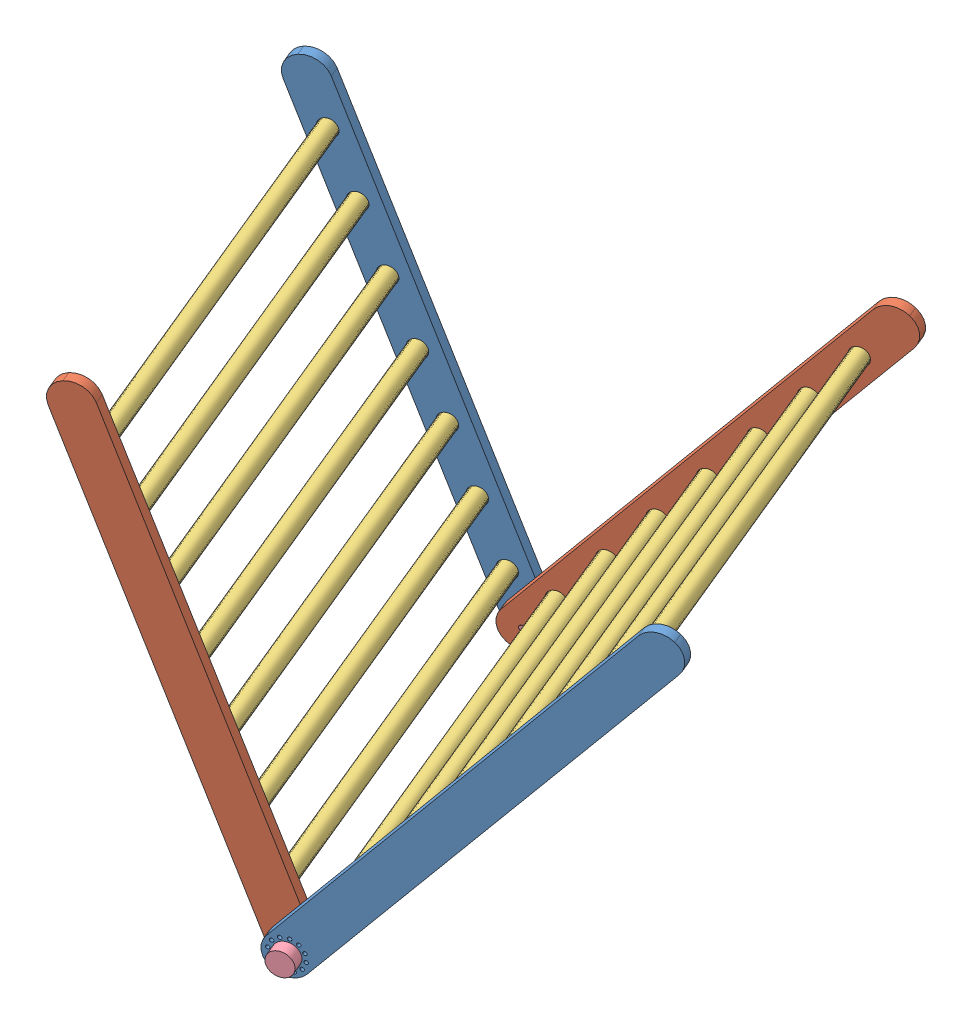
SolidWorks assembly Assembly, configuration Default. Lengths in mm.
Overall size (1185.17 985.62 1062.37).
20 component instances, 4 part files, 28 mates.
Components (placement in the parent):
- Leg Radial Locking Holes-1: Leg Radial Locking Holes [Default] at (-779.6001 -1481.6632 618.7852) x (0.61301 0.769332 -0.179852) z (0.350411 -0.060717 0.934626) size (965.2 76.2 19.05)
- Leg Single Locking Hole-1: Leg Single Locking Hole [Default] at (-758.4501 -1524.0941 587.7167) x (-0.297342 0.939062 0.172485) z (0.350411 -0.060717 0.934626) size (965.2 76.2 19.05)
- Leg Single Locking Hole-3: Leg Single Locking Hole [Default] at (-985.9797 -1485.0135 -98.9733) x (0.61301 0.769332 -0.179852) z (-0.350411 0.060717 -0.934626) size (965.2 76.2 19.05)
- Leg Radial Locking Holes-2: Leg Radial Locking Holes [Default] at (-951.1116 -1453.2027 -130.3621) x (-0.297342 0.939062 0.172485) z (-0.350411 0.060717 -0.934626) size (965.2 76.2 19.05)
- Dowel-2: Dowel [Default] at (-1024.1619 -1352.2175 -106.6048) x (0.936531 0.010997 -0.350411) z (0.350411 -0.060717 0.934626) size (31.75 31.75 762)
- Dowel-3: Dowel [Default] at (-1095.9105 -1125.6219 -64.9842) x (0.936531 0.010997 -0.350411) z (0.350411 -0.060717 0.934626) size (31.75 31.75 762)
- Dowel-4: Dowel [Default] at (-1167.6591 -899.0263 -23.3635) x (0.936531 0.010997 -0.350411) z (0.350411 -0.060717 0.934626) size (31.75 31.75 762)
- Dowel-5: Dowel [Default] at (-1203.5334 -785.7285 -2.5532) x (0.936531 0.010997 -0.350411) z (0.350411 -0.060717 0.934626) size (31.75 31.75 762)
- Dowel-6: Dowel [Default] at (-1239.4077 -672.4307 18.2571) x (0.936531 0.010997 -0.350411) z (0.350411 -0.060717 0.934626) size (31.75 31.75 762)
- Dowel-7: Dowel [Default] at (-1060.0362 -1238.9197 -85.7945) x (0.936531 0.010997 -0.350411) z (0.350411 -0.060717 0.934626) size (31.75 31.75 762)
- Dowel-8: Dowel [Default] at (-1131.7848 -1012.3241 -44.1739) x (0.936531 0.010997 -0.350411) z (0.350411 -0.060717 0.934626) size (31.75 31.75 762)
- knob-1: knob [Default] at (-722.5898 -1477.7383 618.0483) x (-0.928635 -0.152357 0.338268) z (0.350411 -0.060717 0.934626) size (44.45 44.45 60.45)
- knob-2: knob [Default] at (-1002.954 -1429.1587 -129.7457) x (0.546294 -0.797315 -0.256614) z (-0.350411 0.060717 -0.934626) size (44.45 44.45 60.45)
- Dowel-9: Dowel [Default] at (-498.5792 -810.4656 -248.0803) x (0.936531 0.010997 -0.350411) z (0.350411 -0.060717 0.934626) size (31.75 31.75 762)
- Dowel-10: Dowel [Default] at (-572.5388 -903.2855 -226.3812) x (0.936531 0.010997 -0.350411) z (0.350411 -0.060717 0.934626) size (31.75 31.75 762)
- Dowel-11: Dowel [Default] at (-646.4985 -996.1055 -204.6821) x (0.936531 0.010997 -0.350411) z (0.350411 -0.060717 0.934626) size (31.75 31.75 762)
- Dowel-12: Dowel [Default] at (-720.4581 -1088.9254 -182.983) x (0.936531 0.010997 -0.350411) z (0.350411 -0.060717 0.934626) size (31.75 31.75 762)
- Dowel-13: Dowel [Default] at (-794.4177 -1181.7454 -161.2838) x (0.936531 0.010997 -0.350411) z (0.350411 -0.060717 0.934626) size (31.75 31.75 762)
- Dowel-14: Dowel [Default] at (-868.3774 -1274.5653 -139.5847) x (0.936531 0.010997 -0.350411) z (0.350411 -0.060717 0.934626) size (31.75 31.75 762)
- Dowel-15: Dowel [Default] at (-942.337 -1367.3853 -117.8856) x (0.936531 0.010997 -0.350411) z (0.350411 -0.060717 0.934626) size (31.75 31.75 762)
Mates (geometry in assembly coordinates):
- Concentric1: concentric aligned: cylinder of Leg Radial Locking Holes-1 through (-722.5898 -1477.7383 618.0483) axis (-0.350411 0.060717 -0.934626) radius 4.9609; cylinder of Leg Single Locking Hole-1 through (-729.2652 -1476.5816 600.2437) axis (-0.350411 0.060717 -0.934626) radius 4.9609
- Concentric2: concentric aligned: cylinder of Leg Single Locking Hole-3 through (-996.2786 -1430.3153 -111.9411) axis (0.350411 -0.060717 0.934626) radius 4.9609; cylinder of Leg Radial Locking Holes-2 through (-1002.954 -1429.1587 -129.7457) axis (0.350411 -0.060717 0.934626) radius 4.9609
- Coincident3: coincident aligned: cylinder of Leg Radial Locking Holes-1 through (-722.5898 -1477.7383 618.0483) axis (-0.350411 0.060717 -0.934626) radius 4.9609; circle of Leg Radial Locking Holes-2
- Concentric3: concentric anti-aligned: circle of Leg Radial Locking Holes-2; circle of Dowel-2
- Coincident6: coincident anti-aligned: plane of Leg Radial Locking Holes-2 through (-954.4493 -1452.6243 -139.2644) normal (0.350411 -0.060717 0.934626); plane of Dowel-2 through (-1024.1619 -1352.2175 -106.6048) normal (-0.350411 0.060717 -0.934626)
- Coincident7: coincident anti-aligned: plane of Leg Single Locking Hole-1 through (-755.1124 -1524.6725 596.619) normal (-0.350411 0.060717 -0.934626); plane of Dowel-2 through (-757.1484 -1398.4838 605.58) normal (0.350411 -0.060717 0.934626)
- Coincident8: coincident anti-aligned: plane of Leg Radial Locking Holes-2 through (-954.4493 -1452.6243 -139.2644) normal (0.350411 -0.060717 0.934626); plane of Dowel-7 through (-1060.0362 -1238.9197 -85.7945) normal (-0.350411 0.060717 -0.934626)
- Concentric5: concentric anti-aligned: circle of Leg Radial Locking Holes-2; circle of Dowel-7
- Coincident9: coincident anti-aligned: plane of Leg Radial Locking Holes-2 through (-954.4493 -1452.6243 -139.2644) normal (0.350411 -0.060717 0.934626); plane of Dowel-3 through (-1095.9105 -1125.6219 -64.9842) normal (-0.350411 0.060717 -0.934626)
- Concentric6: concentric anti-aligned: circle of Leg Radial Locking Holes-2; circle of Dowel-3
- Coincident10: coincident anti-aligned: plane of Leg Radial Locking Holes-2 through (-954.4493 -1452.6243 -139.2644) normal (0.350411 -0.060717 0.934626); plane of Dowel-8 through (-1131.7848 -1012.3241 -44.1739) normal (-0.350411 0.060717 -0.934626)
- Concentric7: concentric anti-aligned: circle of Leg Radial Locking Holes-2; circle of Dowel-8
- Coincident11: coincident anti-aligned: plane of Leg Radial Locking Holes-2 through (-954.4493 -1452.6243 -139.2644) normal (0.350411 -0.060717 0.934626); plane of Dowel-4 through (-1167.6591 -899.0263 -23.3635) normal (-0.350411 0.060717 -0.934626)
- Concentric8: concentric anti-aligned: circle of Leg Radial Locking Holes-2; circle of Dowel-4
- Coincident13: coincident anti-aligned: plane of Leg Radial Locking Holes-2 through (-954.4493 -1452.6243 -139.2644) normal (0.350411 -0.060717 0.934626); plane of Dowel-5 through (-1203.5334 -785.7285 -2.5532) normal (-0.350411 0.060717 -0.934626)
- Concentric9: concentric anti-aligned: circle of Leg Radial Locking Holes-2; circle of Dowel-5
- Coincident15: coincident anti-aligned: plane of Leg Radial Locking Holes-2 through (-954.4493 -1452.6243 -139.2644) normal (0.350411 -0.060717 0.934626); plane of Dowel-6 through (-1239.4077 -672.4307 18.2571) normal (-0.350411 0.060717 -0.934626)
- Concentric10: concentric anti-aligned: circle of Leg Radial Locking Holes-2; circle of Dowel-6
- Concentric13: concentric aligned: circle of Leg Single Locking Hole-1; circle of knob-1
- Concentric14: concentric aligned: circle of Leg Single Locking Hole-3; circle of knob-2
- Parallel1: parallel aligned: plane of Leg Single Locking Hole-1 through (-763.0279 -1489.7111 612.0491) normal (-0.888144 -0.338344 0.311004); plane of Leg Radial Locking Holes-2 through (-1036.7167 -1442.2881 -117.9403) normal (-0.888144 -0.338344 0.311004)
- Parallel2: parallel aligned: plane of Leg Radial Locking Holes-1 through (-695.7662 -1502.1636 606.4048) normal (0.708118 -0.635957 -0.306803); plane of Leg Single Locking Hole-3 through (-969.4551 -1454.7407 -123.5846) normal (0.708118 -0.635957 -0.306803)
- Concentric19: concentric anti-aligned: circle of Leg Single Locking Hole-3; circle of Dowel-9
- Coincident18: coincident anti-aligned: plane of Leg Single Locking Hole-3 through (-989.3174 -1484.4352 -107.8757) normal (0.350411 -0.060717 0.934626); plane of Dowel-9 through (-498.5792 -810.4656 -248.0803) normal (-0.350411 0.060717 -0.934626)
- Coincident21: coincident anti-aligned: plane of Leg Radial Locking Holes-1 through (-183.9638 -792.6113 440.2318) normal (-0.350411 0.060717 -0.934626); plane of Leg Single Locking Hole-1 through (-993.452 -641.4314 753.5477) normal (0.350411 -0.060717 0.934626)
- Coincident22: coincident anti-aligned: plane of Leg Single Locking Hole-3 through (-451.337 -746.0219 -271.7972) normal (-0.350411 0.060717 -0.934626); plane of Leg Radial Locking Holes-2 through (-1260.9167 -595.337 41.5208) normal (0.350411 -0.060717 0.934626)
- Coincident23: coincident anti-aligned: plane of Leg Radial Locking Holes-1 through (-177.2885 -793.768 458.0364) normal (0.350411 -0.060717 0.934626); plane of knob-1 through (-722.5898 -1477.7383 618.0483) normal (-0.350411 0.060717 -0.934626)
- Coincident24: coincident anti-aligned: plane of Leg Radial Locking Holes-2 through (-1267.592 -594.1803 23.7162) normal (-0.350411 0.060717 -0.934626); plane of knob-2 through (-1002.954 -1429.1587 -129.7457) normal (0.350411 -0.060717 0.934626)
